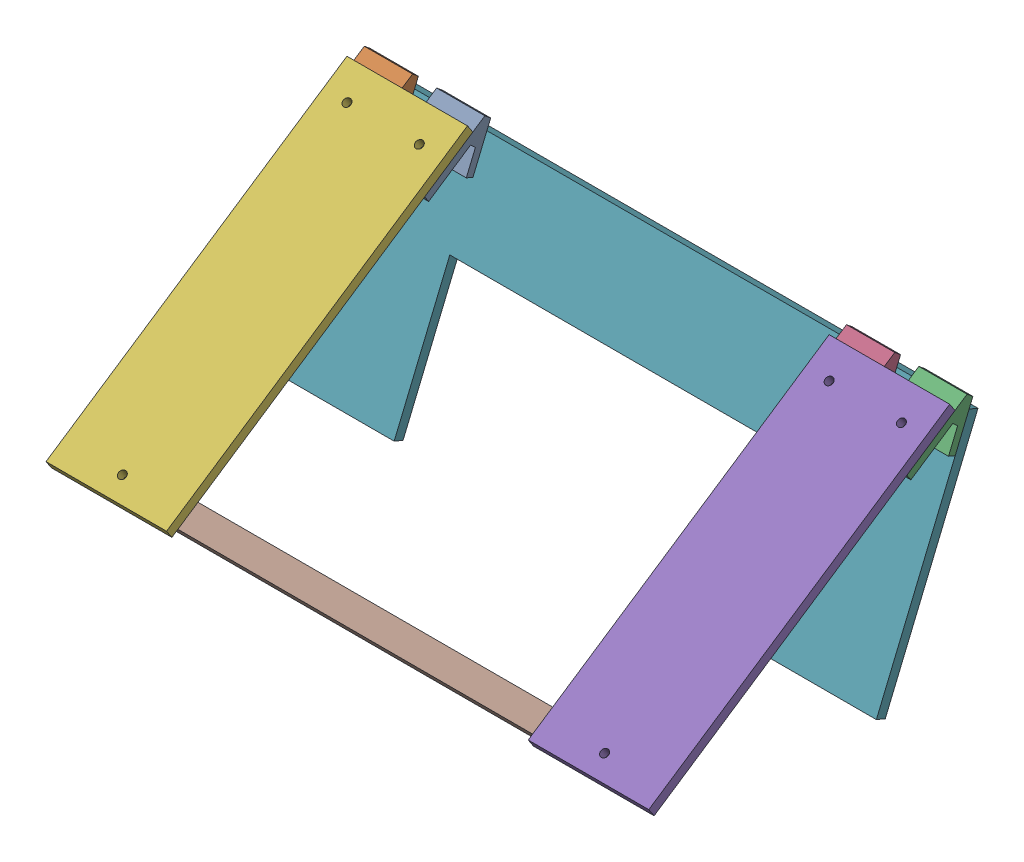
SolidWorks assembly 斜面, configuration 默认. Lengths in mm.
Overall size (250 106.02 136.56).
8 component instances, 4 part files, 32 mates.
Components (placement in the parent):
- 斜坡连接件-1: 斜坡连接件 [默认] at (-152.4441 103.1882 -215.2947) x (0 -0.923077 0.384615) z (0 -0.384615 -0.923077) size (26.62 20 19.64)
- 斜坡连接件-2: 斜坡连接件 [默认] at (-182.4441 103.1882 -215.2947) x (0 -0.923077 0.384615) z (0 -0.384615 -0.923077) size (26.62 20 19.64)
- 斜坡连接件-3: 斜坡连接件 [默认] at (47.5559 103.1881 -215.2946) x (0 -0.923077 0.384615) z (0 -0.384615 -0.923077) size (26.62 20 19.64)
- 斜坡连接件-4: 斜坡连接件 [默认] at (17.5559 103.1881 -215.2946) x (0 -0.923077 0.384615) z (0 -0.384615 -0.923077) size (26.62 20 19.64)
- 斜面_half-1: 斜面_half [默认] at (22.5559 87.545 -69.8267) x (1 0 0) z (0 -0.5547 0.83205) size (50 4 150)
- 斜面_half-2: 斜面_half [默认] at (-177.4441 87.545 -69.8267) x (1 0 0) z (0 -0.5547 0.83205) size (50 4 150)
- 斜坡连接板-2: 斜坡连接板 [默认] at (-77.4441 80.5527 -118.8382) x (1 0 0) z (0 0.923077 -0.384615) size (250 4 100)
- 斜面连接杆-1: 斜面连接杆 [默认] at (-77.4441 47.0519 -16.2981) x (1 0 0) z (0 0.83205 0.5547) size (210 10 4)
Mates (geometry in assembly coordinates):
- 重合1: coincident anti-aligned: plane of 斜坡连接板-1 through (-18.5307 12.4225 0) normal (0 -1 0); plane of 斜坡连接件-2 through (-123.5307 12.4225 -5) normal (0 1 0)
- 同心1: concentric anti-aligned: cylinder of 斜坡连接板-1 through (-133.5307 16.4225 5) axis (0 -1 0) radius 1.6; cylinder of 斜坡连接件-2 through (-133.5307 -1.1677 5) axis (0 1 0) radius 1.6
- 平行2: parallel aligned: plane of 斜坡连接板-1 through (106.4693 16.4225 -15) normal (0 0 -1); plane of 斜坡连接件-2 through (-123.5307 9.4225 -5) normal (0 0 -1)
- 重合5: coincident anti-aligned: plane of 斜坡连接板-1 through (-18.5307 12.4225 0) normal (0 -1 0); plane of 斜坡连接件-1 through (-93.5307 12.4225 -5) normal (0 1 0)
- 平行3: parallel aligned: plane of 斜坡连接板-1 through (106.4693 16.4225 -15) normal (0 0 -1); plane of 斜坡连接件-1 through (-93.5307 9.4225 -5) normal (0 0 -1)
- 同心2: concentric anti-aligned: cylinder of 斜坡连接板-1 through (-103.5307 16.4225 5) axis (0 -1 0) radius 1.6; cylinder of 斜坡连接件-1 through (-103.5307 -1.1677 5) axis (0 1 0) radius 1.6
- 重合7: coincident anti-aligned: plane of 斜坡连接板-1 through (-18.5307 12.4225 0) normal (0 -1 0); plane of 斜坡连接件-4 through (76.4693 12.4225 -5) normal (0 1 0)
- 同心3: concentric anti-aligned: cylinder of 斜坡连接板-1 through (66.4693 16.4225 5) axis (0 -1 0) radius 1.6; cylinder of 斜坡连接件-4 through (66.4693 -1.1677 5) axis (0 1 0) radius 1.6
- 平行4: parallel aligned: plane of 斜坡连接板-1 through (106.4693 16.4225 -15) normal (0 0 -1); plane of 斜坡连接件-4 through (76.4693 9.4225 -5) normal (0 0 -1)
- 重合9: coincident anti-aligned: plane of 斜坡连接板-1 through (-18.5307 12.4225 0) normal (0 -1 0); plane of 斜坡连接件-3 through (106.4693 12.4225 -5) normal (0 1 0)
- 同心4: concentric anti-aligned: cylinder of 斜坡连接板-1 through (96.4693 16.4225 5) axis (0 -1 0) radius 1.6; cylinder of 斜坡连接件-3 through (96.4693 -1.1677 5) axis (0 1 0) radius 1.6
- 平行5: parallel aligned: plane of 斜坡连接板-1 through (106.4693 16.4225 -15) normal (0 0 -1); plane of 斜坡连接件-3 through (106.4693 9.4225 -5) normal (0 0 -1)
- 重合16: coincident anti-aligned: plane of 斜坡连接件-4 through (-2.4441 132.4757 -137.2228) normal (0 0.83205 0.5547); plane of 斜面_half-1 through (22.5559 87.545 -69.8267) normal (0 -0.83205 -0.5547)
- 重合17: coincident anti-aligned: plane of 斜坡连接件-3 through (27.5559 132.4757 -137.2228) normal (0 0.83205 0.5547); plane of 斜面_half-1 through (22.5559 87.545 -69.8267) normal (0 -0.83205 -0.5547)
- 同心8: concentric anti-aligned: cylinder of 斜坡连接件-4 through (7.5559 108.1278 -131.8214) axis (0 0.83205 0.5547) radius 1.6; cylinder of 斜面_half-1 through (7.5559 125.8193 -120.0271) axis (0 -0.83205 -0.5547) radius 1.6
- 同心10: concentric anti-aligned: cylinder of 斜坡连接件-3 through (37.5559 108.1278 -131.8214) axis (0 0.83205 0.5547) radius 1.6; cylinder of 斜面_half-1 through (37.5559 125.8193 -120.0271) axis (0 -0.83205 -0.5547) radius 1.6
- 同心11: concentric anti-aligned: cylinder of 斜坡连接件-4 through (7.5559 108.1278 -131.8214) axis (0 0.83205 0.5547) radius 1.6; cylinder of 斜面_half-1 through (7.5559 125.8193 -120.0271) axis (0 -0.83205 -0.5547) radius 1.6
- 重合20: coincident anti-aligned: plane of 斜坡连接件-2 through (-202.4441 132.4758 -137.2228) normal (0 0.83205 0.5547); plane of 斜面_half-2 through (-177.4441 87.545 -69.8267) normal (0 -0.83205 -0.5547)
- 重合21: coincident anti-aligned: plane of 斜坡连接件-1 through (-172.4441 132.4758 -137.2228) normal (0 0.83205 0.5547); plane of 斜面_half-2 through (-177.4441 87.545 -69.8267) normal (0 -0.83205 -0.5547)
- 平行11: parallel aligned: plane of 斜坡连接件-2 through (-202.4441 115.8348 -112.2613) normal (0 -0.5547 0.83205); plane of 斜面_half-2 through (-152.4441 49.2707 -5.2041) normal (0 -0.5547 0.83205)
- 同心14: concentric aligned: cylinder of 斜坡连接件-1 through (-162.4441 108.1278 -131.8214) axis (0 0.83205 0.5547) radius 1.6; circle of 斜面_half-2
- 相切2: tangent: curve of 斜坡连接件-2; cylinder of 斜面_half-2 through (-192.4441 125.8194 -120.0271) axis (0 -0.83205 -0.5547) radius 1.6
- 同心15: concentric anti-aligned: cylinder of 斜坡连接件-2 through (-192.4441 108.1278 -131.8214) axis (0 0.83205 0.5547) radius 1.6; cylinder of 斜面_half-2 through (-192.4441 125.8194 -120.0271) axis (0 -0.83205 -0.5547) radius 1.6
- 重合27: coincident anti-aligned: plane of 斜坡连接件-2 through (-202.4441 130.4835 -139.6427) normal (0 -0.384615 -0.923077); plane of 斜坡连接板-2 through (-77.4441 80.5527 -118.8382) normal (0 0.384615 0.923077)
- 同心16: concentric aligned: cylinder of 斜坡连接件-2 through (-192.4441 117.4758 -134.2228) axis (0 0.384615 0.923077) radius 1.6; cylinder of 斜坡连接板-2 through (-192.4441 115.9373 -137.9151) axis (0 0.384615 0.923077) radius 1.6
- 同心17: concentric aligned: cylinder of 斜坡连接件-1 through (-162.4441 117.4758 -134.2228) axis (0 0.384615 0.923077) radius 1.6; cylinder of 斜坡连接板-2 through (-162.4441 115.9373 -137.9151) axis (0 0.384615 0.923077) radius 1.6
- 重合28: coincident anti-aligned: plane of 斜坡连接件-3 through (27.5559 130.4834 -139.6426) normal (0 -0.384615 -0.923077); plane of 斜坡连接板-2 through (-77.4441 80.5527 -118.8382) normal (0 0.384615 0.923077)
- 重合29: coincident aligned: circle of 斜坡连接件-3; cylinder of 斜坡连接板-2 through (37.5559 115.9372 -137.9151) axis (0 0.384615 0.923077) radius 1.6
- 同心18: concentric aligned: cylinder of 斜坡连接件-4 through (7.5559 117.4757 -134.2228) axis (0 0.384615 0.923077) radius 1.6; cylinder of 斜坡连接板-2 through (7.5559 115.9372 -137.9151) axis (0 0.384615 0.923077) radius 1.6
- 重合30: coincident anti-aligned: plane of 斜面_half-1 through (22.5559 87.545 -69.8267) normal (0 -0.83205 -0.5547); plane of 斜面连接杆-1 through (-77.4441 50.3801 -14.0793) normal (0 0.83205 0.5547)
- 同心19: concentric aligned: cylinder of 斜面_half-2 through (-177.4441 53.7083 -11.8605) axis (0 -0.83205 -0.5547) radius 1.6; cylinder of 斜面连接杆-1 through (-177.4441 50.3801 -14.0793) axis (0 -0.83205 -0.5547) radius 1.6
- 同心20: concentric anti-aligned: circle of 斜面_half-1; cylinder of 斜面连接杆-1 through (22.5559 50.3801 -14.0793) axis (0 -0.83205 -0.5547) radius 1.6
